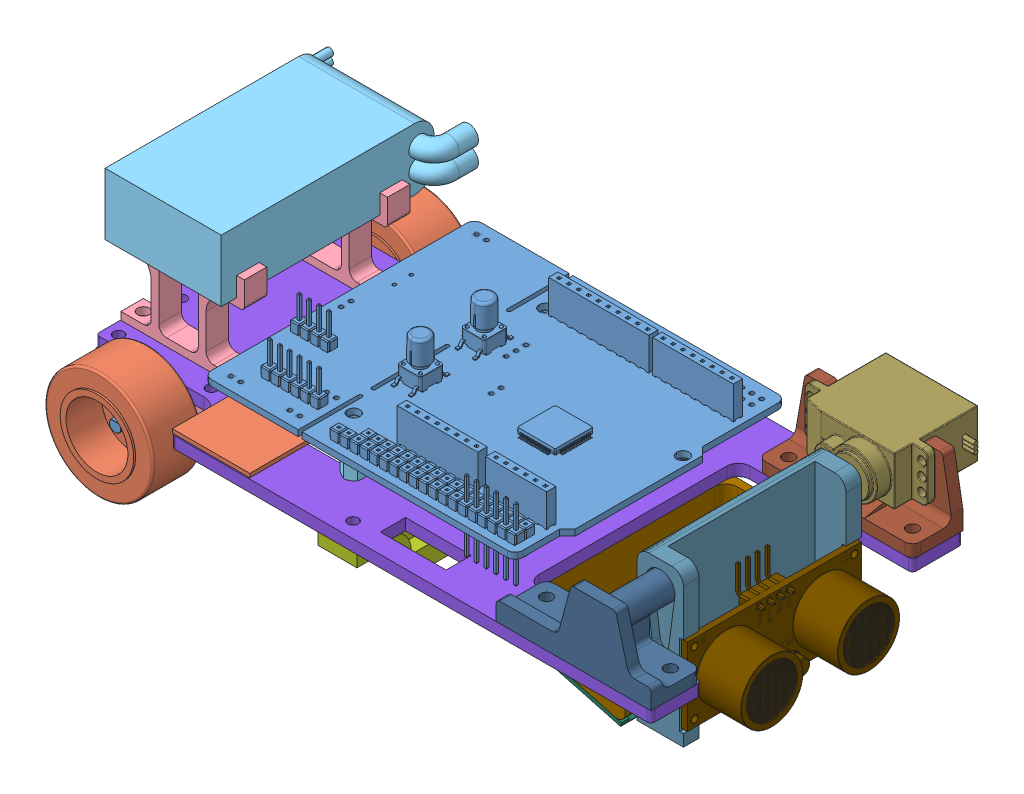
SolidWorks assembly Vehicle Assy V4, configuration Default. Lengths in mm.
Overall size (162.5 58 94.8).
36 component instances, 24 part files, 63 mates.
Components (placement in the parent):
- Drive Unit Assy-1: Drive Unit Assy [Default] at origin size (30 27.94 40.5)
  - Micro Metal Gearmotor HP 6V-1: Micro Metal Gearmotor HP 6V [Default] at origin size (12 10.04 35.8)
  - Wheel-1: Wheel [Default] at (0 0 10.5) size (27.94 27.94 13.7)
  - Inner Motor Bracket-1: Inner Motor Bracket [Default] at (0 0 -10.1) size (30 12 5.8)
  - Outer Motor Bracket-1: Outer Motor Bracket [Default] at (0 0 6.1) size (30 12 5.8)
- Drive Unit Assy-2: Drive Unit Assy [Default] at (0 0 -37.6) x (-1 0 0) z (0 0 -1) size (30 27.94 40.5)
  - Micro Metal Gearmotor HP 6V-1: Micro Metal Gearmotor HP 6V [Default] at origin size (12 10.04 35.8)
  - Wheel-1: Wheel [Default] at (0 0 10.5) size (27.94 27.94 13.7)
  - Inner Motor Bracket-1: Inner Motor Bracket [Default] at (0 0 -10.1) size (30 12 5.8)
  - Outer Motor Bracket-1: Outer Motor Bracket [Default] at (0 0 6.1) size (30 12 5.8)
- NUCLEO-F401RE-1: NUCLEO-F401RE [Default] at (51.4773 18.3838 -20.6911) size (70 20.7 83.95) (hidden)
- 6V LiPO Battery-1: 6V LiPO Battery [Default] at (0 28 -20.9228) x (0 0 -1) z (1 0 0) size (60 16 39.5)
- TCS34725 Color Sensor-1: TCS34725 Color Sensor [Default] at (52.4 -6.5 -34.8083) x (0 0 1) z (-1 0 0) size (20 2.5 20)
- TCS34725 Color Sensor-2: TCS34725 Color Sensor [Default] at (52.4 -6.5 -2.7917) x (0 0 1) z (-1 0 0) size (20 2.5 20)
- Color Sensor Bracket-2: Color Sensor Bracket [Default] at (60 -2 -18.8) x (0 0 -1) z (1 0 0) size (80.6 12 15)
- Chassis Plate-1: Chassis Plate [Default] at (-15 5 -18.8) size (156 3 80.6)
- Capture Mechanism Assy-2: Capture Mechanism Assy [Default] at (128 -13 -18.8) size (57 39.73 92.6)
  - Bucket-2: Bucket [Default] at origin size (36 17.39 52)
  - Trapdoor Clevis-3: Trapdoor Clevis [Default] at (-7 32.75 37.3) x (-1 0 0) z (0 0 1) size (40 17.75 19)
  - Servo Clevis-4: Servo Clevis [Default] at (-7 32.75 -37.3) x (1 0 0) z (0 0 -1) size (40 17.75 13)
  - SM-S2309S Servo-3: SM-S2309S Servo [Défaut] at (-7 39 -52.3) x (1 0 0) z (0 -1 0) size (31.8 29.3 12.5)
  - Servo Attachment-4: Servo Attachment [Default] at (-1.9 32.75 -21) x (-1 0 0) z (0 0 -1) size (7 17.5 4)
  - Trapdoor-4: Trapdoor [Default] at (-1.9 32.75 0) x (-1 0 0) z (0 0 -1) size (12 39 46)
  - Bucket Ramp-1: Bucket Ramp [Default] at (-21.5724 3.1191 0) x (0.965926 -0.258819 0) z (0 0 1) size (26 1 52)
- Ball Caster-1: Ball Caster [Default] at (78.5 2 -18.8) x (0 0 1) z (-1 0 0) size (26 16 26)
- Caster Spacer-1: Caster Spacer [Default] at (79.3553 2 -18.8) size (24.29 3 26.5)
- HC-SR04 Ultrasonic Sensor-1: HC-SR04 Ultrasonic Sensor [Default] at (131.1 0.25 -18.8) x (0 0 1) z (1 0 0) size (45 25.83 17.8)
- NUCLEO-F401RE-6: NUCLEO-F401RE [Default] at (62.85 20 -17.27) x (0 0 -1) z (1 0 0) size (70 20.7 83.95)
- Perfboard-1: Perfboard [Default] at (27 8 -18.8) x (0 0 -1) z (1 0 0) size (80 1 20)
- DRV8835 Dual Motor Driver Carrier-3: DRV8835 Dual Motor Driver Carrier [Default] at (17.7427 5 -13.72) x (0 0 -1) z (0 -1 0) size (10.16 17.78 2.83)
- Battery Mount-1: Battery Mount [Default] at (0 8 -40.2) size (34 25 5.8)
- Battery Mount-2: Battery Mount [Default] at (0 8 -3.2) size (34 25 5.8)
- M2.5x0.45 Standoff, 12mm Length (95947A007)-1: M2.5x0.45 Standoff, 12mm Length (95947A007) [95947A007] at (49.53 8 6.86) x (0 1 0) z (0 0 1) size (12.34 4.5 5.2)
- M2.5x0.45 Standoff, 12mm Length (95947A007)-2: M2.5x0.45 Standoff, 12mm Length (95947A007) [95947A007] at (50.8 8 -41.4) x (0 1 0) z (0 0 1) size (12.34 4.5 5.2)
- M2.5x0.45 Screw (92005A069)-1: M2.5x0.45 Screw (92005A069) [92005A069] at (88 4 -40.8) x (1 0 0) z (0 1 0) size (5 5 10.18)
- M2.5x0.45 Screw (92005A069)-2: M2.5x0.45 Screw (92005A069) [92005A069] at (88 4 3.2) x (1 0 0) z (0 1 0) size (5 5 10.18)
Mates (geometry in assembly coordinates):
- Width1: width: plane of Capture Mechanism Assy-1/Bucket-1 through (86.5 5 8.2) normal (0 0 1); plane of Capture Mechanism Assy-1/Bucket-1 through (107.5 5 -45.8) normal (0 0 -1); plane of Drive Unit Assy-2/Wheel-1 through (0 0 -60.8) normal (0 0 -1); plane of Drive Unit Assy-1/Wheel-1 through (0 0 23.2) normal (0 0 1)
- Coincident1: coincident: plane of Drive Unit Assy-2/Outer Motor Bracket-1 through (15 5 -46.6) normal (0 1 0); plane of Capture Mechanism Assy-1/Bucket-1 through (86.5 5 -39.8) normal (0 1 0)
- Width2: width anti-aligned: plane of Color Sensor Bracket-1 through (19.7307 43.8959 9.2) normal (0 0 1); plane of Drive Unit Assy-2/Wheel-1 through (19.7307 40.8959 -46.8) normal (0 0 -1); plane of Color Sensor Bracket-1 through (0 0 -60.8) normal (0 0 -1); plane of Drive Unit Assy-1/Wheel-1 through (0 0 23.2) normal (0 0 1)
- Coincident8: coincident aligned: plane of Drive Unit Assy-2/Outer Motor Bracket-1 through (15 5 -46.6) normal (0 1 0); plane of Color Sensor Bracket-2 through (65 5 -59.1) normal (0 1 0)
- Width5: width anti-aligned: plane of Color Sensor Bracket-2 through (65 2 -59.1) normal (0 0 -1); plane of Color Sensor Bracket-2 through (65 2 21.5) normal (0 0 1); plane of Drive Unit Assy-1/Wheel-1 through (0 0 23.2) normal (0 0 1); plane of Drive Unit Assy-2/Wheel-1 through (0 0 -60.8) normal (0 0 -1)
- Slot5: slot anti-aligned: cylinder of TCS34725 Color Sensor-1 through (60 -5 -27.2083) axis (0 -1 0) radius 1.27; plane of Color Sensor Bracket-2 through (61.4 -5 4.8) normal (-1 0 0); cylinder of Color Sensor Bracket-2 through (60 -5 -42.4) axis (0 1 0) radius 1.4
- Slot6: slot anti-aligned: cylinder of TCS34725 Color Sensor-2 through (60 -5 -10.3917) axis (0 -1 0) radius 1.27; plane of Color Sensor Bracket-2 through (61.4 -5 4.8) normal (-1 0 0); cylinder of Color Sensor Bracket-2 through (60 -5 -42.4) axis (0 1 0) radius 1.4
- Parallel3: parallel aligned: plane of TCS34725 Color Sensor-2 through (62.4 -5 -10.7917) normal (1 0 0); plane of Color Sensor Bracket-2 through (65 -1 13.5) normal (1 0 0)
- Parallel4: parallel aligned: plane of TCS34725 Color Sensor-1 through (62.4 -5 -42.8083) normal (1 0 0); plane of Color Sensor Bracket-2 through (65 -1 13.5) normal (1 0 0)
- Coincident10: coincident anti-aligned: plane of TCS34725 Color Sensor-1 through (60.4 -5 -42.8083) normal (0 1 0); plane of Color Sensor Bracket-2 through (65 -5 9.5) normal (0 -1 0)
- Coincident11: coincident anti-aligned: plane of TCS34725 Color Sensor-2 through (60.4 -5 -10.7917) normal (0 1 0); plane of Color Sensor Bracket-2 through (65 -5 9.5) normal (0 -1 0)
- Width6: width anti-aligned: plane of TCS34725 Color Sensor-1 through (44.4 -5 -24.8083) normal (0 0 1); plane of TCS34725 Color Sensor-2 through (44.4 -5 -12.7917) normal (0 0 -1); plane of Color Sensor Bracket-2 through (55 -2.6 -15.1) normal (0 0 -1); plane of Color Sensor Bracket-2 through (55 -2.6 -22.5) normal (0 0 1)
- Concentric2: concentric aligned: cylinder of Drive Unit Assy-1/Outer Motor Bracket-1 through (-12 -7 6.1) axis (0 1 0) radius 1.5; cylinder of Chassis Plate-1 through (-12 5 6.1) axis (0 1 0) radius 1.35
- Concentric3: concentric aligned: cylinder of Drive Unit Assy-2/Outer Motor Bracket-1 through (-12 -7 -43.7) axis (0 1 0) radius 1.5; cylinder of Chassis Plate-1 through (-12 5 -43.7) axis (0 1 0) radius 1.35
- Coincident12: coincident anti-aligned: circle of Drive Unit Assy-2/Outer Motor Bracket-1; plane of Chassis Plate-1 through (-15 5 -18.8) normal (0 -1 0)
- Concentric4: concentric: cylinder of Capture Mechanism Assy-1/Bucket-1 through (74.5 3 -6.8) axis (0 1 0) radius 1.5; cylinder of Chassis Plate-1 through (88 5 3.2) axis (0 1 0) radius 1.35
- Concentric5: concentric: cylinder of Capture Mechanism Assy-1/Bucket-1 through (74.5 3 -30.8) axis (0 1 0) radius 1.5; cylinder of Chassis Plate-1 through (88 5 -40.8) axis (0 1 0) radius 1.35
- Concentric6: concentric aligned: cylinder of Chassis Plate-1 through (88 5 3.2) axis (0 1 0) radius 1.35; cylinder of Capture Mechanism Assy-2/Bucket-1 through (74.5 3 3.7) axis (0 1 0) radius 1.5
- Concentric7: concentric aligned: cylinder of Chassis Plate-1 through (88 5 -40.8) axis (0 1 0) radius 1.35; cylinder of Capture Mechanism Assy-2/Bucket-1 through (74.5 3 -41.3) axis (0 1 0) radius 1.5
- Coincident13: coincident anti-aligned: plane of Chassis Plate-1 through (-15 5 -18.8) normal (0 -1 0); plane of Capture Mechanism Assy-2/Bucket-1 through (86.5 5 -39.3) normal (0 1 0)
- Coincident14: coincident anti-aligned: plane of Drive Unit Assy-1/Outer Motor Bracket-1 through (-15 5 9) normal (0 1 0); plane of Chassis Plate-1 through (-15 5 -18.8) normal (0 -1 0)
- Concentric11: concentric aligned: cylinder of Drive Unit Assy-2/Inner Motor Bracket-1 through (-12 -7 -27.5) axis (0 1 0) radius 1.5; cylinder of Chassis Plate-1 through (-12 5 -27.5) axis (0 1 0) radius 1.35
- Concentric12: concentric aligned: cylinder of Drive Unit Assy-1/Inner Motor Bracket-1 through (-12 -7 -10.1) axis (0 1 0) radius 1.5; cylinder of Chassis Plate-1 through (-12 5 -10.1) axis (0 1 0) radius 1.35
- Concentric13: concentric aligned: cylinder of Color Sensor Bracket-2 through (60 -5.001 17.5) axis (0 1 0) radius 1.5; cylinder of Chassis Plate-1 through (60 5 17.5) axis (0 1 0) radius 1.35
- Coincident15: coincident anti-aligned: plane of Chassis Plate-1 through (-15 5 -18.8) normal (0 -1 0); plane of DRV8835 Dual Motor Driver Carrier-2 through (15.876 5 -27.69) normal (0 1 0)
- Width7: width anti-aligned: plane of DRV8835 Dual Motor Driver Carrier-2 through (26.036 3.984 -9.91) normal (0 0 1); plane of DRV8835 Dual Motor Driver Carrier-2 through (15.876 3.984 -27.69) normal (0 0 -1); plane of Drive Unit Assy-2/Wheel-1 through (0 0 -60.8) normal (0 0 -1); plane of Drive Unit Assy-1/Wheel-1 through (0 0 23.2) normal (0 0 1)
- Distance1: distance = 11 mm anti-aligned: plane of NUCLEO-F401RE-2 through (87.5213 19 -3.0744) normal (0 -1 0); plane of Chassis Plate-1 through (-15 8 -18.8) normal (0 1 0)
- Distance2: distance = 11 mm anti-aligned: plane of NUCLEO-F401RE-4 through (74.0761 19 53.8738) normal (0 -1 0); plane of Chassis Plate-1 through (-15 8 -18.8) normal (0 1 0)
- Concentric18: concentric aligned: cylinder of Chassis Plate-1 through (88 5 3.2) axis (0 1 0) radius 1.35; cylinder of Capture Mechanism Assy-2/Bucket-2 through (88 3 3.2) axis (0 1 0) radius 1.5
- Concentric19: concentric aligned: cylinder of Chassis Plate-1 through (88 5 -40.8) axis (0 1 0) radius 1.35; cylinder of Capture Mechanism Assy-2/Bucket-2 through (88 3 -40.8) axis (0 1 0) radius 1.5
- Coincident19: coincident anti-aligned: plane of Chassis Plate-1 through (-15 5 -18.8) normal (0 -1 0); plane of Capture Mechanism Assy-2/Bucket-2 through (99 5 -39.8) normal (0 1 0)
- Width8: width anti-aligned: plane of Perfboard-1 through (37 9 -58.8) normal (0 0 -1); plane of Drive Unit Assy-1/Wheel-1 through (37 9 21.2) normal (0 0 1); plane of Perfboard-1 through (0 0 23.2) normal (0 0 1); plane of Drive Unit Assy-2/Wheel-1 through (0 0 -60.8) normal (0 0 -1)
- Coincident20: coincident anti-aligned: plane of Chassis Plate-1 through (-15 8 -18.8) normal (0 1 0); plane of Perfboard-1 through (27 8 -18.8) normal (0 -1 0)
- Distance3: distance = 12 mm anti-aligned: plane of NUCLEO-F401RE-6 through (152.94 20 15.73) normal (0 -1 0); plane of Chassis Plate-1 through (-15 8 -18.8) normal (0 1 0)
- Width9: width anti-aligned: plane of DRV8835 Dual Motor Driver Carrier-3 through (17.7427 3.984 -23.88) normal (0 0 -1); plane of Drive Unit Assy-1/Wheel-1 through (35.5227 3.984 -13.72) normal (0 0 1); plane of DRV8835 Dual Motor Driver Carrier-3 through (0 0 23.2) normal (0 0 1); plane of Drive Unit Assy-2/Wheel-1 through (0 0 -60.8) normal (0 0 -1)
- Coincident22: coincident anti-aligned: plane of Chassis Plate-1 through (-15 5 -18.8) normal (0 -1 0); plane of DRV8835 Dual Motor Driver Carrier-3 through (17.7427 5 -13.72) normal (0 1 0)
- Concentric20: concentric aligned: cylinder of Chassis Plate-1 through (-12 5 -37.3) axis (0 1 0) radius 1.35; cylinder of Battery Mount-1 through (-12 8 -37.3) axis (0 1 0) radius 1.5
- Concentric21: concentric aligned: cylinder of Chassis Plate-1 through (12 5 -37.3) axis (0 1 0) radius 1.35; cylinder of Battery Mount-1 through (12 8 -37.3) axis (0 1 0) radius 1.5
- Concentric22: concentric aligned: cylinder of Chassis Plate-1 through (-12 5 -0.3) axis (0 1 0) radius 1.35; cylinder of Battery Mount-2 through (-12 8 -0.3) axis (0 1 0) radius 1.5
- Concentric23: concentric aligned: cylinder of Chassis Plate-1 through (12 5 -0.3) axis (0 1 0) radius 1.35; cylinder of Battery Mount-2 through (12 8 -0.3) axis (0 1 0) radius 1.5
- Coincident24: coincident anti-aligned: plane of Chassis Plate-1 through (-15 8 -18.8) normal (0 1 0); plane of Battery Mount-2 through (-14.9 8 2.6) normal (0 -1 0)
- Coincident25: coincident anti-aligned: plane of Chassis Plate-1 through (-15 8 -18.8) normal (0 1 0); plane of Battery Mount-1 through (-14.9 8 -34.4) normal (0 -1 0)
- Width10: width aligned: plane of 6V LiPO Battery-1 through (-15 44 6.5772) normal (-1 0 0); plane of Battery Mount-1 through (15 44 6.5772) normal (1 0 0); plane of 6V LiPO Battery-1 through (15 28 -34.4) normal (-1 0 0); plane of Battery Mount-1 through (-15 33 -34.4) normal (1 0 0)
- Coincident26: coincident anti-aligned: plane of 6V LiPO Battery-1 through (0 28 -20.9228) normal (0 -1 0); plane of Battery Mount-1 through (-15 28 -34.4) normal (0 1 0)
- Concentric24: concentric aligned: cylinder of Chassis Plate-1 through (50.8 5 -41.4) axis (0 1 0) radius 1.5; cylinder of NUCLEO-F401RE-6 through (50.8 20 -41.4) axis (0 1 0) radius 1.6
- Concentric25: concentric aligned: cylinder of Chassis Plate-1 through (49.53 5 6.86) axis (0 1 0) radius 1.5; cylinder of NUCLEO-F401RE-6 through (49.53 20 6.86) axis (0 1 0) radius 1.6
- Coincident27: coincident aligned: plane of Chassis Plate-1 through (17 8 9) normal (-1 0 0); plane of Perfboard-1 through (17 9 21.2) normal (-1 0 0)
- Concentric26: concentric anti-aligned: cylinder of Chassis Plate-1 through (49.53 5 6.86) axis (0 1 0) radius 1.5; circle of M2.5x0.45 Standoff, 12mm Length (95947A007)-1
- Coincident28: coincident anti-aligned: plane of Chassis Plate-1 through (-15 8 -18.8) normal (0 1 0); plane of M2.5x0.45 Standoff, 12mm Length (95947A007)-1 through (49.53 8 6.86) normal (0 -1 0)
- Concentric27: concentric anti-aligned: cylinder of Chassis Plate-1 through (50.8 5 -41.4) axis (0 1 0) radius 1.5; circle of M2.5x0.45 Standoff, 12mm Length (95947A007)-2
- Coincident29: coincident anti-aligned: plane of Chassis Plate-1 through (-15 8 -18.8) normal (0 1 0); plane of M2.5x0.45 Standoff, 12mm Length (95947A007)-2 through (50.8 8 -41.4) normal (0 -1 0)
- Concentric28: concentric aligned: circle of Chassis Plate-1; circle of M2.5x0.45 Screw (92005A069)-1
- Coincident30: coincident anti-aligned: plane of Chassis Plate-1 through (-15 8 -18.8) normal (0 1 0); plane of M2.5x0.45 Screw (92005A069)-1 through (88 8 -38.7609) normal (0 -1 0)
- Concentric29: concentric aligned: circle of Chassis Plate-1; circle of M2.5x0.45 Screw (92005A069)-2
- Coincident31: coincident anti-aligned: plane of Chassis Plate-1 through (-15 8 -18.8) normal (0 1 0); plane of M2.5x0.45 Screw (92005A069)-2 through (88 8 5.2391) normal (0 -1 0)
- Width11: width: plane of HC-SR04 Ultrasonic Sensor-1 through (142.0153 10.25 -41.3) normal (0 0 -1); plane of Capture Mechanism Assy-2/Trapdoor-4 through (142.0153 -9.75 3.7) normal (0 0 1); plane of HC-SR04 Ultrasonic Sensor-1 through (132.1 -13.25 4.2) normal (0 0 1); plane of Capture Mechanism Assy-2/Trapdoor-4 through (120.1 -13.25 -41.8) normal (0 0 -1)
- Concentric30: concentric anti-aligned: cylinder of Chassis Plate-1 through (86.5 5 -18.8) axis (0 1 0) radius 1.75; cylinder of Caster Spacer-1 through (86.5 5 -18.8) axis (0 -1 0) radius 1.75
- Concentric31: concentric anti-aligned: cylinder of Chassis Plate-1 through (72.2106 5 -27.05) axis (0 1 0) radius 1.75; cylinder of Caster Spacer-1 through (72.2106 5 -27.05) axis (0 -1 0) radius 1.75
- Concentric32: concentric anti-aligned: cylinder of Chassis Plate-1 through (72.2106 5 -10.55) axis (0 1 0) radius 1.75; cylinder of Caster Spacer-1 through (72.2106 5 -10.55) axis (0 -1 0) radius 1.75
- Coincident32: coincident anti-aligned: plane of Chassis Plate-1 through (-15 5 -18.8) normal (0 -1 0); plane of Caster Spacer-1 through (72.2106 5 -27.05) normal (0 1 0)
- Width12: width: plane of HC-SR04 Ultrasonic Sensor-1 through (142.0153 10.25 3.7) normal (0 1 0); plane of Capture Mechanism Assy-2/Trapdoor-4 through (142.0153 -9.75 -41.3) normal (0 -1 0); plane of HC-SR04 Ultrasonic Sensor-1 through (131.1 10.75 4.2) normal (0 -1 0); plane of Capture Mechanism Assy-2/Trapdoor-4 through (131.1 -10.25 4.2) normal (0 1 0)
- Width13: width: plane of HC-SR04 Ultrasonic Sensor-1 through (131.1 10.25 -41.3) normal (0 0 -1); plane of Capture Mechanism Assy-2/Trapdoor-4 through (131.1 -9.75 3.7) normal (0 0 1); plane of HC-SR04 Ultrasonic Sensor-1 through (132.1 -13.25 4.2) normal (0 0 1); plane of Capture Mechanism Assy-2/Trapdoor-4 through (120.1 -13.25 -41.8) normal (0 0 -1)
- Coincident33: coincident anti-aligned: plane of Capture Mechanism Assy-2/Trapdoor-4 through (131.1 19.75 -18.8) normal (1 0 0); plane of HC-SR04 Ultrasonic Sensor-1 through (131.1 0.25 -18.8) normal (-1 0 0)
